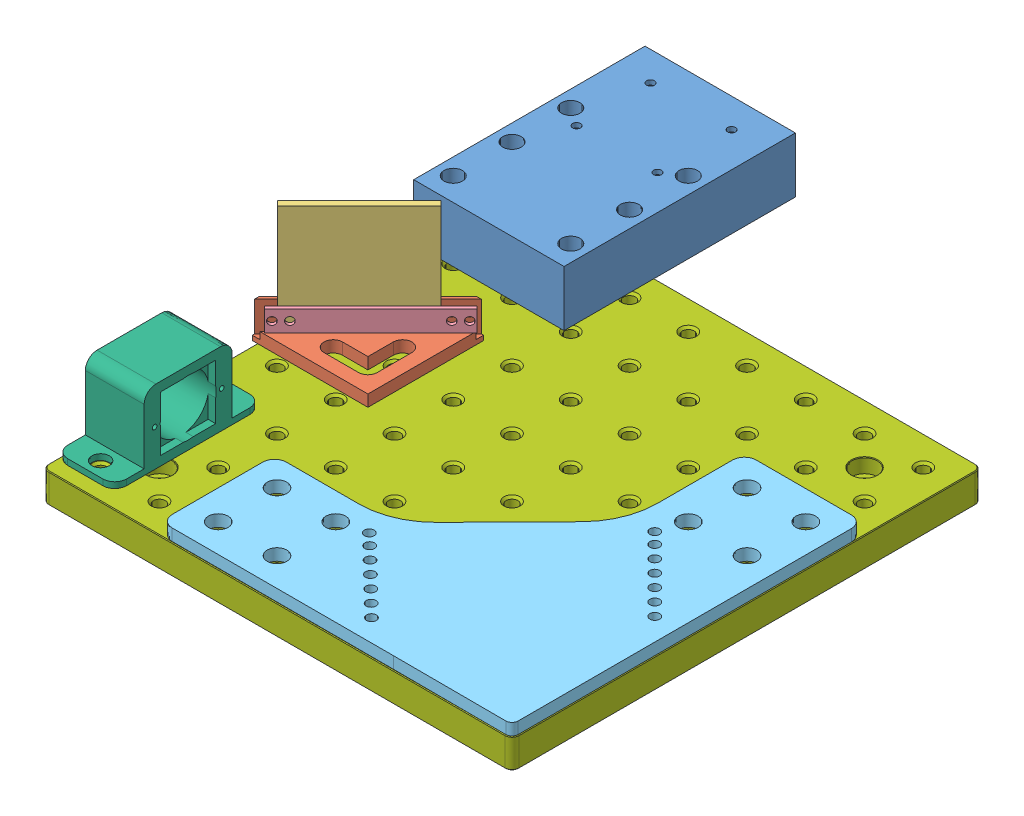
SolidWorks assembly Assem2, configuration Default. Lengths in mm.
Overall size (205.27 64.95 255.12).
8 component instances, 7 part files, 9 mates.
Components (placement in the parent):
- LRFh-1: LRFh [Default] at (25.2629 129.9578 42.3248) size (65 24 100)
- beamsplitter-1: beamsplitter [Default] at (10.0967 120.9578 129.4426) x (0 0 1) z (-1 0 0) size (50 15 50)
- beamspliitert1-1: beamspliitert1 [Default] at (9.8455 147.9578 132.9365) x (-0.707107 0 0.707107) z (-0.707107 0 -0.707107) size (50 50 3)
- bs hold-1: bs hold [Default] at (12.3532 130.9578 130.4288) x (0.707107 0 -0.707107) z (0.707107 0 0.707107) size (65 9 1.5)
- ldass-1: ldass [Default] at (85.0818 150.2975 110.9783) x (-1 0 0) z (0 0.999999 -0.001223) size (203.48 203.22 44.54)
  - Part 1-1: Part 1 [Default] at (-11.2978 96.6361 -29.458) x (1 0 0) z (0 0.001223 0.999999) size (152.1 151.8 5.08)
  - Part 1_1-1: Part 1_1 [Default] at (72.7954 98.3429 -13.585) x (0 0.999999 -0.001223) z (0 0.001223 0.999999) size (63.5 25.4 31.75)
  - Part 1_3-1: Part 1_3 [Default] at (-3.681 34.7951 -42.0823) x (1 0 0) z (0 -0.999999 0.001223) size (203.2 12.7 203.21)
Mates (geometry in assembly coordinates):
- Coincident2: coincident anti-aligned: plane of beamsplitter-1 through (-14.9033 135.9578 153.4426) normal (0.707107 0 0.707107); plane of beamspliitert1-1 through (7.7242 147.9578 130.8152) normal (-0.707107 0 -0.707107)
- Coincident4: coincident anti-aligned: plane of beamsplitter-1 through (10.0967 122.9578 129.4426) normal (0 1 0); plane of beamspliitert1-1 through (25.4018 122.9578 113.1375) normal (0 -1 0)
- Distance3: distance = 7 mm: line of beamspliitert1-1 through (-9.9535 122.9578 148.4929) axis (0 1 0); line of beamsplitter-1 through (-14.9033 135.9578 153.4426) axis (0 -1 0)
- Concentric6: concentric aligned: cylinder of beamsplitter-1 through (14.3419 130.9578 175.1974) axis (-0.707107 0 -0.707107) radius 1.65; cylinder of bs hold-1 through (-7.9761 130.9578 152.8794) axis (-0.707107 0 -0.707107) radius 1.65
- Coincident8: coincident anti-aligned: plane of beamspliitert1-1 through (9.8455 147.9578 132.9365) normal (0.707107 0 0.707107); plane of bs hold-1 through (12.3532 130.9578 130.4288) normal (-0.707107 0 -0.707107)
- Concentric10: concentric aligned: cylinder of LRFh-1 through (-0.1371 134.9578 82.3248) axis (0 -1 0) radius 4; cylinder of ldass-1/Part 1_3-1 through (-0.1371 120.9578 82.3248) axis (0 -1 0) radius 2.5527
- Concentric11: concentric aligned: cylinder of LRFh-1 through (50.6629 134.9578 56.9248) axis (0 -1 0) radius 4; cylinder of ldass-1/Part 1_3-1 through (50.6629 120.9578 56.9248) axis (0 -1 0) radius 2.5527
- Distance6: distance = 0 mm anti-aligned: plane of beamsplitter-1 through (10.0967 120.9578 129.4426) normal (0 -1 0); plane of ldass-1/Part 1_3-1 through (187.3629 120.9578 47.2248) normal (0 1 0)
- Distance7: distance = 9 mm anti-aligned: plane of LRFh-1 through (25.2629 129.9578 42.3248) normal (0 -1 0); plane of ldass-1/Part 1_3-1 through (187.3629 120.9578 47.2248) normal (0 1 0)
